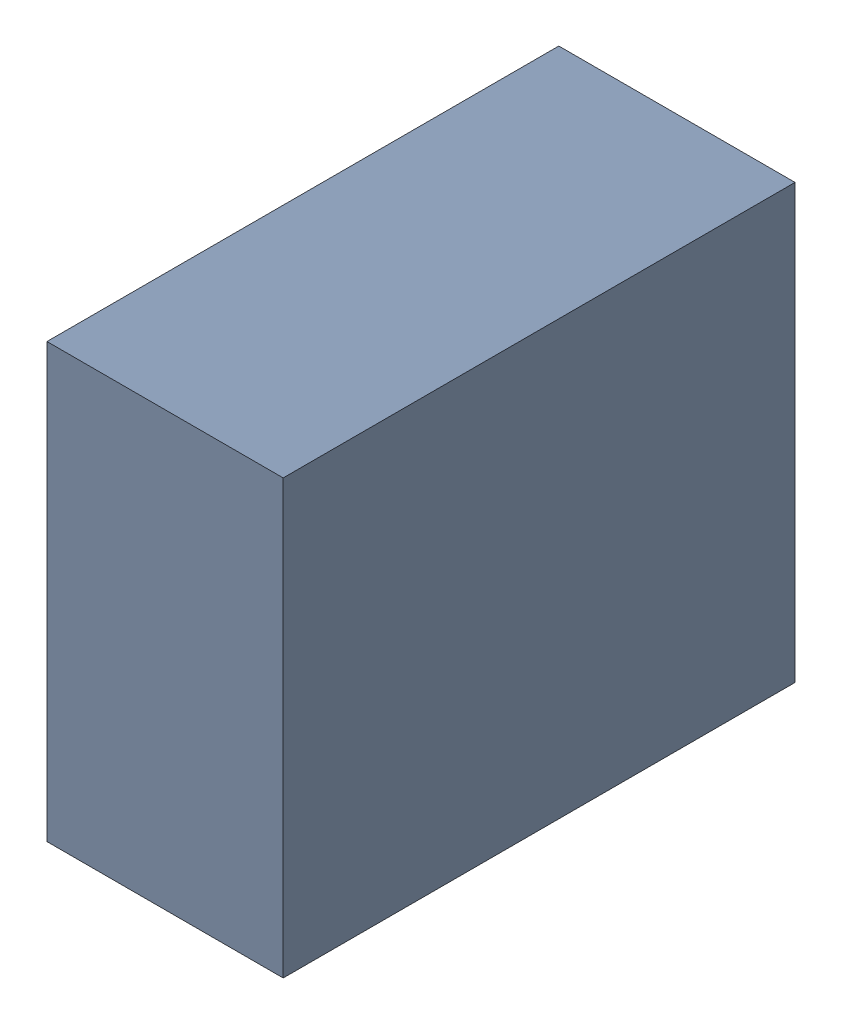
SolidWorks assembly C7, configuration Standard. Lengths in mm.
Overall size (0.6 1.1 1.3).
2 component instances, 1 part files, 0 mates.
Components (placement in the parent):
- 885542376-1: 885542376 [Standard] at (7.5 -2.9 0) size (0.6 1.1 1.3)
  - Extruded_25-1: Extruded_25 [Standard] at origin size (0.6 1.1 1.3)
